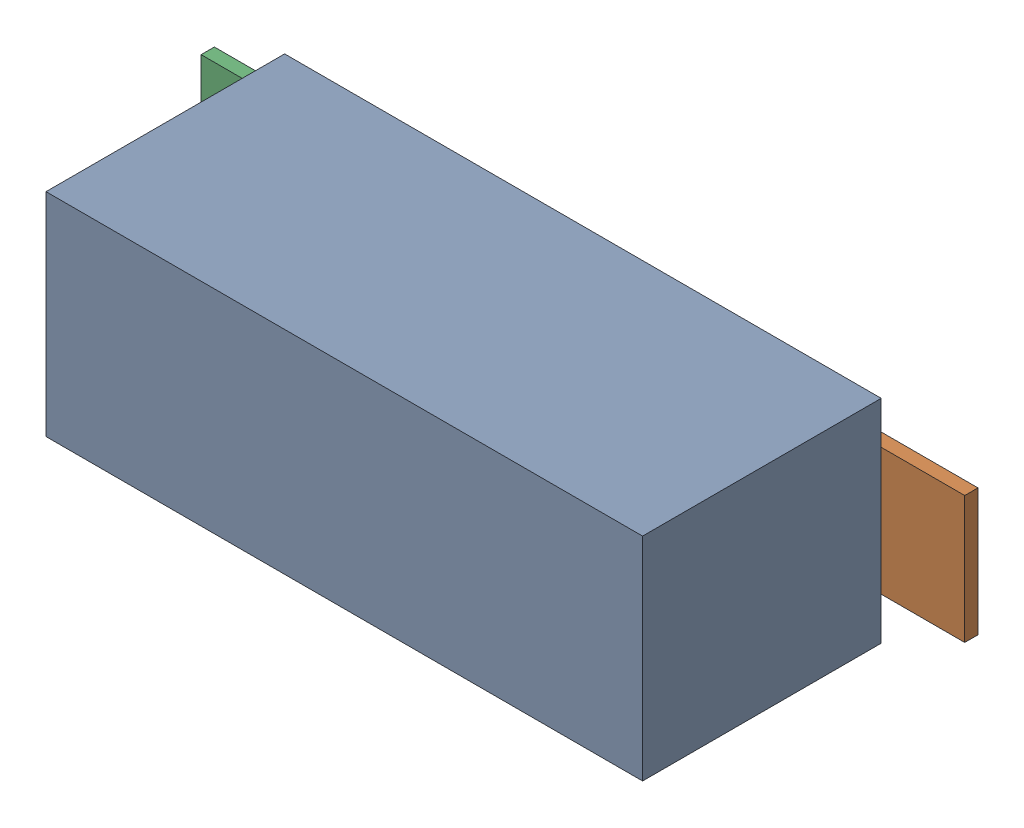
SolidWorks assembly TROYKA_AMPLIFIER_D__INDC4509X190N, configuration По умолчанию. Lengths in mm.
Overall size (5.76 1.6 1.9).
3 component instances, 2 part files, 0 mates.
Components (placement in the parent):
- TROYKA_AMPLIFIER_D__BLM41PG102SZ1B v1-1: TROYKA_AMPLIFIER_D__BLM41PG102SZ1B v1 [По умолчанию] at origin size (5.76 1.6 1.9)
  - TROYKA_AMPLIFIER_D_Body-1: TROYKA_AMPLIFIER_D_Body [По умолчанию] at (0 0 0.1) size (4.5 1.6 1.8)
  - TROYKA_AMPLIFIER_D_Pins-1: TROYKA_AMPLIFIER_D_Pins [По умолчанию] at origin size (5.76 0.96 0.1)
